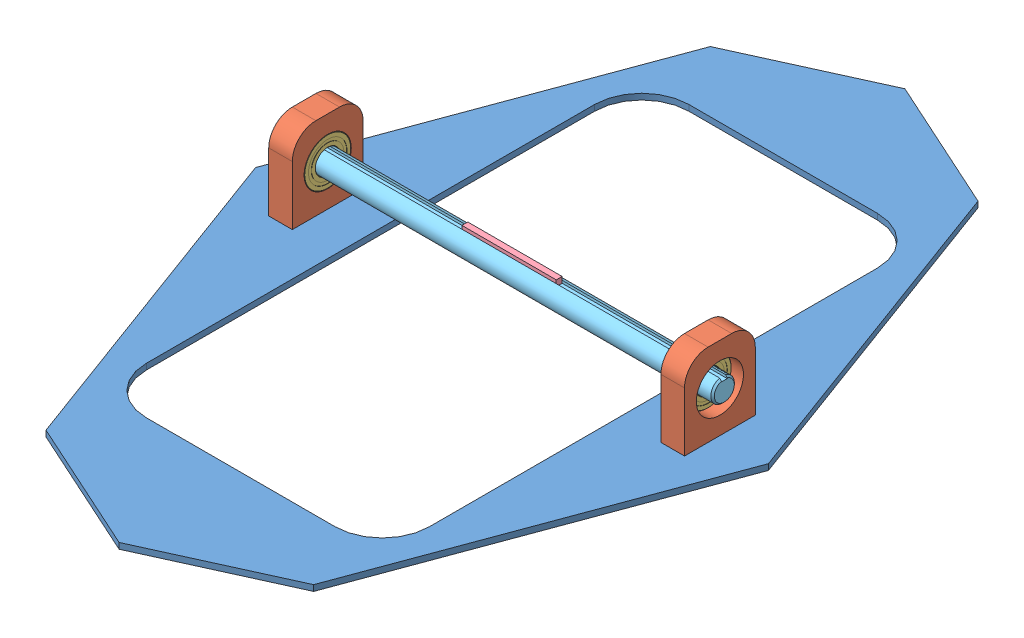
SolidWorks assembly SubAssembly_PendCylMount, configuration Default. Lengths in mm.
Overall size (552.22 95.25 846.08).
7 component instances, 5 part files, 15 mates.
Components (placement in the parent):
- Platform_Octagon_Pend-1: Platform_Octagon_Pend [Default] at origin size (552.22 6.35 846.08)
- BearingMount_Pend-1: BearingMount_Pend [Default] at (-211.1375 47.625 0) x (0 0 1) z (-1 0 0) size (76.2 88.9 25.4)
- BearingMount_Pend-2: BearingMount_Pend [Default] at (211.1375 47.625 0) x (0 0 1) z (-1 0 0) size (76.2 88.9 25.4)
- 60355K708_BALL BEARING-1: 60355K708_BALL BEARING [60355K708] at (204.7875 47.625 0) x (0 0 -1) z (1 0 0) size (50.8 50.8 12.7)
- 60355K708_BALL BEARING-2: 60355K708_BALL BEARING [60355K708] at (-204.7875 47.625 0) x (0 0 1) z (-1 0 0) size (50.8 50.8 12.7)
- Keystock-1: Keystock [Default] at (0 60.325 0) size (101.6 6.35 6.35)
- 1497K281_FULLY KEYED 1045 STEEL DRIVE SHAFT-1: 1497K281_FULLY KEYED 1045 STEEL DRIVE SHAFT [1497K281] at (0 47.625 0) size (457.2 25.4 25.4)
Mates (geometry in assembly coordinates):
- Concentric1: concentric aligned: cylinder of Platform_Octagon_Pend-1 through (-203.2 3.175 -19.05) axis (0 -1 0) radius 2.54; cylinder of BearingMount_Pend-1 through (-203.2 3.175 -19.05) axis (0 -1 0) radius 2.0193
- Concentric2: concentric aligned: cylinder of Platform_Octagon_Pend-1 through (-219.075 3.175 -19.05) axis (0 -1 0) radius 2.54; cylinder of BearingMount_Pend-1 through (-219.075 3.175 -19.05) axis (0 -1 0) radius 2.0193
- Coincident1: coincident anti-aligned: plane of Platform_Octagon_Pend-1 through (0 3.175 0) normal (0 1 0); plane of BearingMount_Pend-1 through (-223.8375 3.175 38.1) normal (0 -1 0)
- Concentric3: concentric aligned: cylinder of Platform_Octagon_Pend-1 through (203.2 3.175 19.05) axis (0 -1 0) radius 2.54; cylinder of BearingMount_Pend-2 through (203.2 3.175 19.05) axis (0 -1 0) radius 2.0193
- Concentric4: concentric aligned: cylinder of Platform_Octagon_Pend-1 through (219.075 3.175 19.05) axis (0 -1 0) radius 2.54; cylinder of BearingMount_Pend-2 through (219.075 3.175 19.05) axis (0 -1 0) radius 2.0193
- Coincident2: coincident anti-aligned: plane of Platform_Octagon_Pend-1 through (0 3.175 0) normal (0 1 0); plane of BearingMount_Pend-2 through (198.4375 3.175 38.1) normal (0 -1 0)
- Concentric5: concentric aligned: cylinder of BearingMount_Pend-2 through (198.4375 47.625 0) axis (1 0 0) radius 25.4; cylinder of 60355K708_BALL BEARING-1 through (211.1375 47.625 0) axis (1 0 0) radius 25.4
- Coincident3: coincident aligned: plane of BearingMount_Pend-2 through (198.4375 66.675 12.7) normal (-1 0 0); plane of 60355K708_BALL BEARING-1 through (198.4375 72.39 0) normal (-1 0 0)
- Concentric6: concentric anti-aligned: cylinder of BearingMount_Pend-1 through (-223.8375 47.625 0) axis (1 0 0) radius 25.4; cylinder of 60355K708_BALL BEARING-2 through (-211.1375 47.625 0) axis (-1 0 0) radius 25.4
- Coincident4: coincident aligned: plane of BearingMount_Pend-1 through (-198.4375 66.675 12.7) normal (1 0 0); plane of 60355K708_BALL BEARING-2 through (-198.4375 72.39 0) normal (1 0 0)
- Coincident5: coincident: plane of Keystock-1 through (33.6199 57.15 -3.175) normal (0 0 -1); plane of 1497K281_FULLY KEYED 1045 STEEL DRIVE SHAFT-1 through (-228.6 60.325 -3.175) normal (0 0 1)
- Coincident6: coincident: plane of Keystock-1 through (33.6199 57.15 -3.175) normal (0 -1 0); plane of 1497K281_FULLY KEYED 1045 STEEL DRIVE SHAFT-1 through (-228.6 57.15 3.175) normal (0 1 0)
- Concentric7: concentric aligned: cylinder of 60355K708_BALL BEARING-2 through (-211.1375 47.625 0) axis (-1 0 0) radius 12.7; cylinder of 1497K281_FULLY KEYED 1045 STEEL DRIVE SHAFT-1 through (228.6 47.625 0) axis (-1 0 0) radius 12.7
- Width1: width anti-aligned: plane of 1497K281_FULLY KEYED 1045 STEEL DRIVE SHAFT-1 through (-228.6 47.625 0) normal (-1 0 0); plane of 1497K281_FULLY KEYED 1045 STEEL DRIVE SHAFT-1 through (228.6 47.625 0) normal (1 0 0); plane of BearingMount_Pend-2 through (223.8375 66.675 12.7) normal (1 0 0); plane of BearingMount_Pend-1 through (-223.8375 66.675 12.7) normal (-1 0 0)
- Width2: width anti-aligned: plane of Keystock-1 through (-50.8 60.325 0) normal (-1 0 0); plane of Keystock-1 through (50.8 60.325 0) normal (1 0 0); plane of 1497K281_FULLY KEYED 1045 STEEL DRIVE SHAFT-1 through (228.6 47.625 0) normal (1 0 0); plane of 1497K281_FULLY KEYED 1045 STEEL DRIVE SHAFT-1 through (-228.6 47.625 0) normal (-1 0 0)
